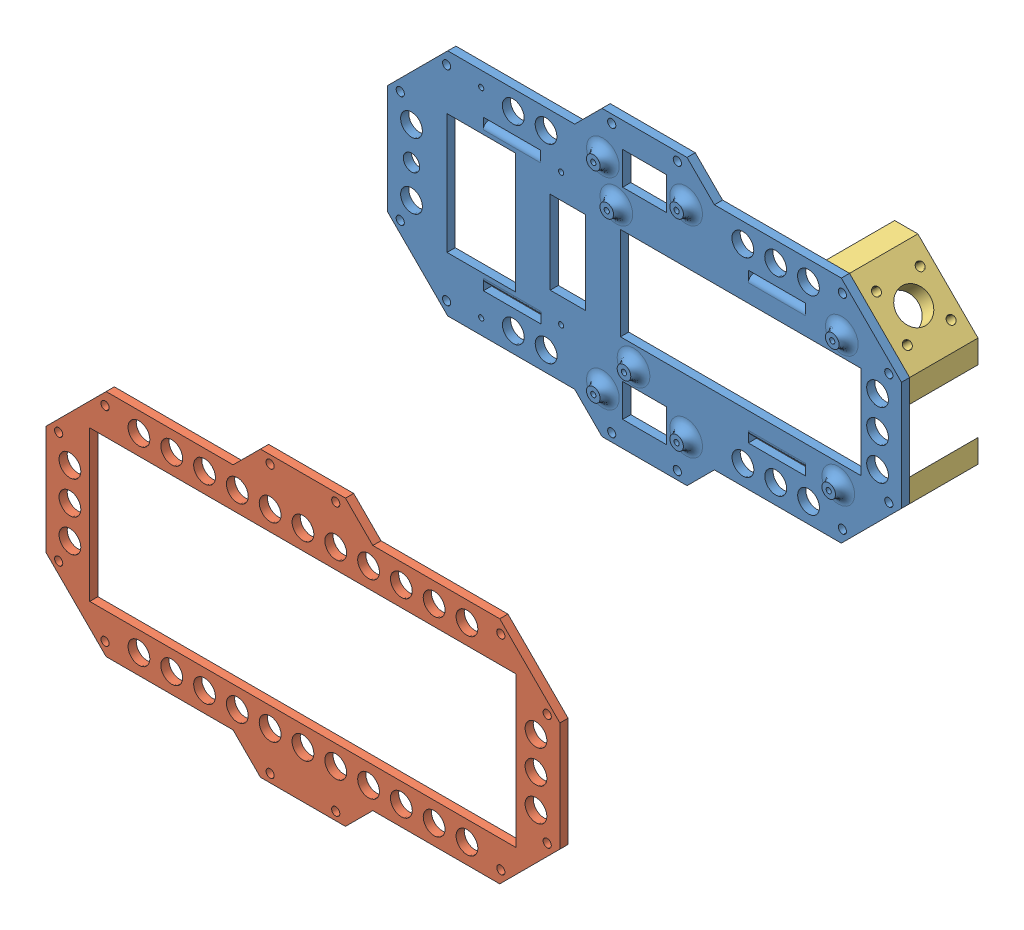
SolidWorks assembly LIUZU_00, configuration 默认. Lengths in mm.
Overall size (282.18 243.65 58.78).
4 component instances, 3 part files, 6 mates.
Components (placement in the parent):
- Assembly - Body-7-1: Assembly - Body-7 [默认] at (-8.5722 9.5723 172.25) size (188 104 6.5)
- Assembly - Body-8-1: Assembly - Body-8 [默认] at (-102.7514 -130.0735 231.0309) size (188 104 3)
- Assembly - Body-13-1: Assembly - Body-13 [默认] at (-8.5722 9.5723 172.25) x (-1 0 0) z (0 0 1) size (30.49 30.49 25)
- Assembly - Body-13-2: Assembly - Body-13 [默认] at (43.4278 61.5723 172.25) x (0 1 0) z (0 0 1) size (30.49 30.49 25)
Mates (geometry in assembly coordinates):
- 重合1: coincident: plane of Assembly - Body-7-1 through (-8.5722 9.5723 184.75) normal (0 0 -1); plane of Assembly - Body-13-1 through (70.1851 36.3297 184.75) normal (0 0 1)
- 同心1: concentric: cylinder of Assembly - Body-7-1 through (80.7917 29.9657 184.75) axis (0 0 1) radius 1.5; cylinder of Assembly - Body-13-1 through (80.7917 29.9657 172.25) axis (0 0 1) radius 1.13
- 同心2: concentric: cylinder of Assembly - Body-7-1 through (63.8212 46.9363 184.75) axis (0 0 1) radius 1.5; cylinder of Assembly - Body-13-1 through (63.8212 46.9363 172.25) axis (0 0 1) radius 1.13
- 重合2: coincident: plane of Assembly - Body-7-1 through (-8.5722 9.5723 184.75) normal (0 0 -1); plane of Assembly - Body-13-2 through (70.1851 -17.185 184.75) normal (0 0 1)
- 同心3: concentric: cylinder of Assembly - Body-7-1 through (80.7917 -10.8211 184.75) axis (0 0 1) radius 1.5; cylinder of Assembly - Body-13-2 through (80.7917 -10.8211 172.25) axis (0 0 1) radius 1.13
- 同心4: concentric: cylinder of Assembly - Body-7-1 through (63.8212 -27.7916 184.75) axis (0 0 1) radius 1.5; cylinder of Assembly - Body-13-2 through (63.8212 -27.7916 172.25) axis (0 0 1) radius 1.13
